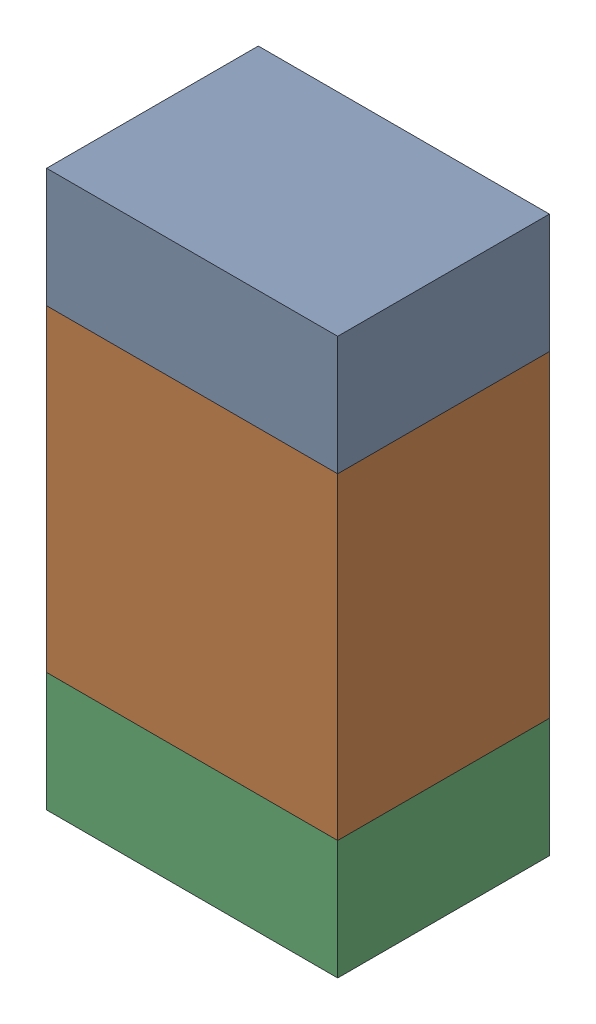
SolidWorks assembly R110_2PCB, configuration Default. Lengths in mm.
Overall size (0.55 1.05 0.4).
6 component instances, 2 part files, 0 mates.
Components (placement in the parent):
- 846483288-1: 846483288 [Default] at (115.7001 94.1124 0) size (0.55 0.22 0.4)
  - Extruded_12-1: Extruded_12 [Default] at origin size (0.55 0.22 0.4)
- 846483424-1: 846483424 [Default] at (115.7001 93.6999 0) size (0.55 0.6 0.4)
  - Extruded_13-1: Extruded_13 [Default] at origin size (0.55 0.6 0.4)
- 846483288-2: 846483288 [Default] at (115.7001 93.2874 0) size (0.55 0.22 0.4)
  - Extruded_12-1: Extruded_12 [Default] at origin size (0.55 0.22 0.4)
